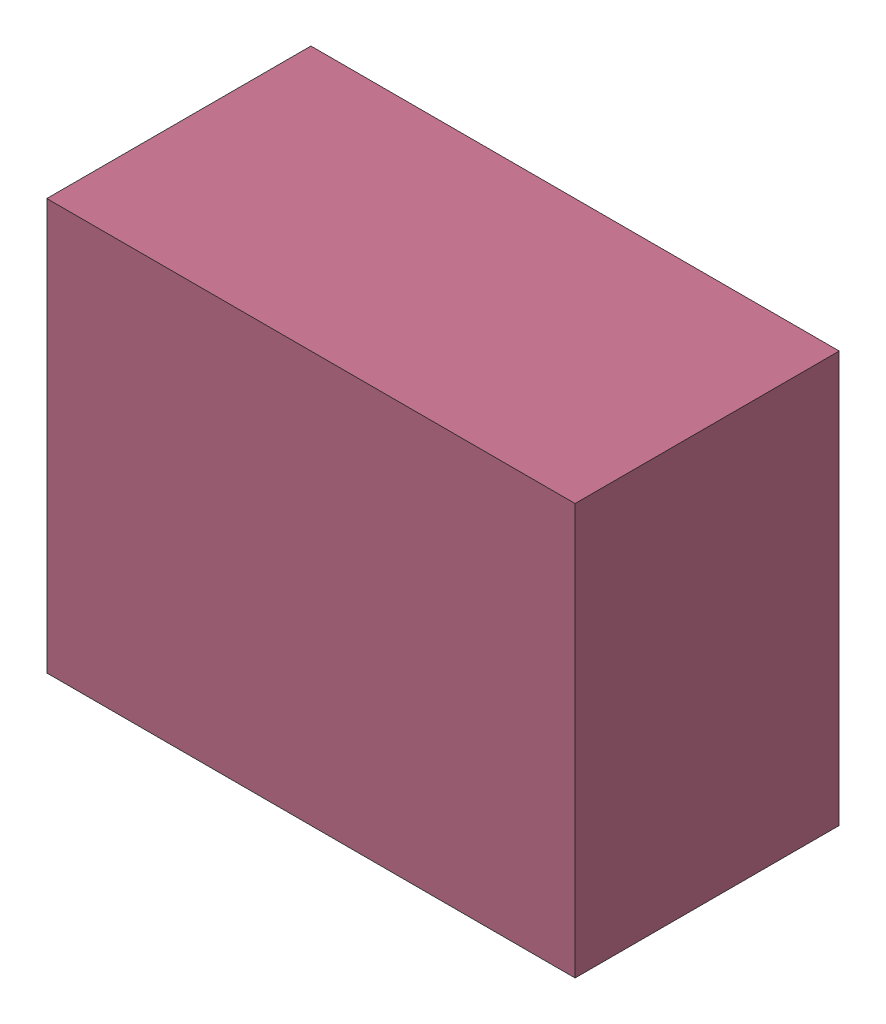
SolidWorks assembly LED1Kanaloa_v2.0.0_GPIO_b, configuration Default. Lengths in mm.
Overall size (3.6 2.8 1.8).
8 component instances, 3 part files, 0 mates.
Components (placement in the parent):
- 352877648-1: 352877648 [Default] at (107.966 28.829 0) size (0.38 1.3 0.85)
  - Extruded_14-1: Extruded_14 [Default] at origin size (0.38 1.3 0.85)
- 352877904-1: 352877904 [Default] at (108.966 28.829 0) size (2.2 1.27 0.85)
  - Extruded_18-1: Extruded_18 [Default] at origin size (2.2 1.27 0.85)
- 352877648-2: 352877648 [Default] at (109.966 28.829 0) size (0.38 1.3 0.85)
  - Extruded_14-1: Extruded_14 [Default] at origin size (0.38 1.3 0.85)
- 352878544-1: 352878544 [Default] at (108.966 28.829 0) size (3.6 2.8 1.8)
  - Extruded_6-1: Extruded_6 [Default] at origin size (3.6 2.8 1.8)
